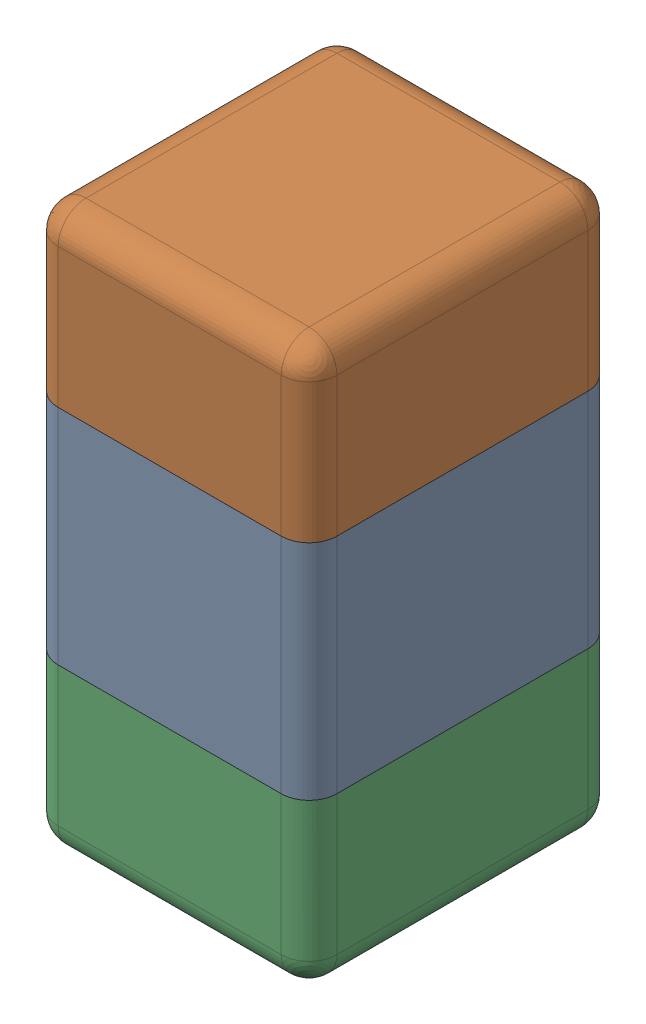
SolidWorks assembly C10, configuration Default. Lengths in mm.
Overall size (0.51 1.01 0.56).
5 component instances, 4 part files, 0 mates.
Components (placement in the parent):
- Cap_Kemet_C0402C562J5RACTU_eec-1: Cap_Kemet_C0402C562J5RACTU_eec [Default] at (147.25 90 -1.6914) x (0 -1 0) z (0 0 -1) size (1.01 0.51 0.56)
  - body_2-1: body_2 [Default] at origin size (0.4 0.5 0.55)
  - terminals-1: terminals [Default] at origin size (0.31 0.51 0.56)
  - terminals_2-1: terminals_2 [Default] at origin size (0.31 0.51 0.56)
  - value-1: value [Default] at (0 0 0.55) size (0.37 0.29 0.15)
